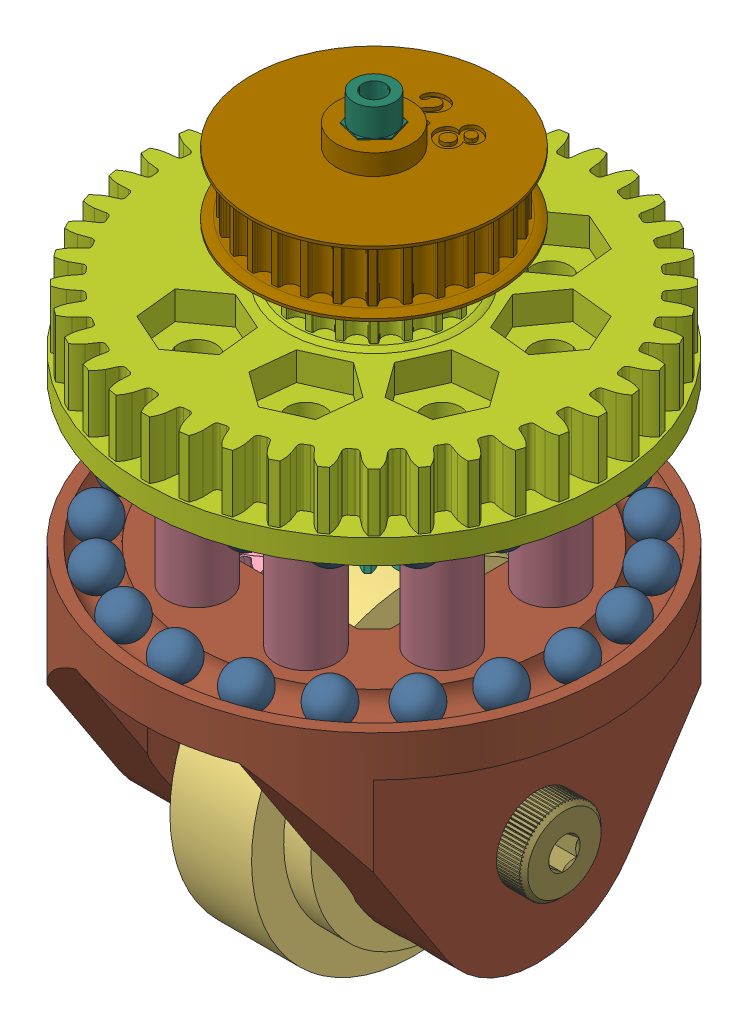
SolidWorks assembly Coaxial-Swerve Inner Modual Test Assem, configuration Default. Lengths in mm.
Overall size (53.98 92.63 53.98).
65 component instances, 18 part files, 64 mates.
Components (placement in the parent):
- Coaxial-Swerve test-1: Coaxial-Swerve test [Default] at origin size (78.17 85.72 76.44) (hidden)
- 57155K352_Stainless Steel Ball Bearing-1: 57155K352_Stainless Steel Ball Bearing [57155K352] at (-12.7 7.6375 0) x (1 0 0) z (0 -1 0) size (7.94 7.94 2.78)
- 60355K502_Ball Bearing-1: 60355K502_Ball Bearing [60355K502] at (-12.7 39.0049 0) x (1 0 0) z (0 -1 0) size (12.7 12.7 3.97)
- wheel bevel gear-2: wheel bevel gear [Hub and Gear] at (-5.2165 0 0) x (-1 0 0) z (0 -0.800175 0.599767) size (17.39 32.09 32.09)
- wheel bevel pinion-2: wheel bevel pinion [Inch - Straight bevel pinion 32DP15PT 40GT 20PA .25FW ---15O3H.063MD0.1875N] at (-12.7 16.1735 0) x (0 -1 0) z (0.960661 0 -0.277724) size (7.15 13.7 13.78)
- Inside Powered Gear-1: Inside Powered Gear [Default] at (-12.7 28.575 0) x (-0.277724 0 -0.960661) z (0 1 0) size (14.29 14.36 13.21)
- Inside Powering Pinion-1: Inside Powering Pinion [Default] at (0 28.575 0) x (-0.686506 0 0.727124) z (0 1 0) size (14.29 14.36 24.33)
- Swivel Base Gear-1: Swivel Base Gear [Default] at (0 41.783 0) x (0 0 1) z (0 1 0) size (53.98 53.98 14.13)
- 60355K503_Ball Bearing (1)-1: 60355K503_Ball Bearing (1) [60355K503] at (0 44.0563 0) x (1 0 0) z (0 -1 0) size (15.88 15.88 4.98)
- Above Driven Pully-1: Above Driven Pully [Default] at (0 56.515 0) x (0.972961 0 0.23097) z (-0.23097 0 0.972961) size (28.62 10.01 28.62)
- 9613K15_Wear-Resistant Nylon Balls-1: 9613K15_Wear-Resistant Nylon Balls [9613K15] at (-23.1902 20.3835 0) x (0.958311 0.024656 0.284661) z (-0.285108 0.016955 0.958346) size (4.76 4.76 4.76)
- 9613K15_Wear-Resistant Nylon Balls-2: 9613K15_Wear-Resistant Nylon Balls [9613K15] at (-23.1902 36.7665 0) size (4.76 4.76 4.76)
- 9613K15_Wear-Resistant Nylon Balls-3: 9613K15_Wear-Resistant Nylon Balls [9613K15] at (-22.0552 36.7665 7.1662) x (0.951057 0 -0.309017) z (0.309017 0 0.951057) size (4.76 4.76 4.76)
- 9613K15_Wear-Resistant Nylon Balls-4: 9613K15_Wear-Resistant Nylon Balls [9613K15] at (-18.7613 36.7665 13.6309) x (0.809017 0 -0.587785) z (0.587785 0 0.809017) size (4.76 4.76 4.76)
- 9613K15_Wear-Resistant Nylon Balls-5: 9613K15_Wear-Resistant Nylon Balls [9613K15] at (-13.6309 36.7665 18.7613) x (0.587785 0 -0.809017) z (0.809017 0 0.587785) size (4.76 4.76 4.76)
- 9613K15_Wear-Resistant Nylon Balls-6: 9613K15_Wear-Resistant Nylon Balls [9613K15] at (-7.1662 36.7665 22.0552) x (0.309017 0 -0.951057) z (0.951057 0 0.309017) size (4.76 4.76 4.76)
- 9613K15_Wear-Resistant Nylon Balls-7: 9613K15_Wear-Resistant Nylon Balls [9613K15] at (0 36.7665 23.1902) x (0 0 -1) z (1 0 0) size (4.76 4.76 4.76)
- 9613K15_Wear-Resistant Nylon Balls-8: 9613K15_Wear-Resistant Nylon Balls [9613K15] at (7.1662 36.7665 22.0552) x (-0.309017 0 -0.951057) z (0.951057 0 -0.309017) size (4.76 4.76 4.76)
- 9613K15_Wear-Resistant Nylon Balls-9: 9613K15_Wear-Resistant Nylon Balls [9613K15] at (13.6309 36.7665 18.7613) x (-0.587785 0 -0.809017) z (0.809017 0 -0.587785) size (4.76 4.76 4.76)
- 9613K15_Wear-Resistant Nylon Balls-10: 9613K15_Wear-Resistant Nylon Balls [9613K15] at (18.7613 36.7665 13.6309) x (-0.809017 0 -0.587785) z (0.587785 0 -0.809017) size (4.76 4.76 4.76)
- 9613K15_Wear-Resistant Nylon Balls-11: 9613K15_Wear-Resistant Nylon Balls [9613K15] at (22.0552 36.7665 7.1662) x (-0.951057 0 -0.309017) z (0.309017 0 -0.951057) size (4.76 4.76 4.76)
- 9613K15_Wear-Resistant Nylon Balls-12: 9613K15_Wear-Resistant Nylon Balls [9613K15] at (23.1902 36.7665 0) x (-1 0 0) z (0 0 -1) size (4.76 4.76 4.76)
- 9613K15_Wear-Resistant Nylon Balls-13: 9613K15_Wear-Resistant Nylon Balls [9613K15] at (22.0552 36.7665 -7.1662) x (-0.951057 0 0.309017) z (-0.309017 0 -0.951057) size (4.76 4.76 4.76)
- 9613K15_Wear-Resistant Nylon Balls-14: 9613K15_Wear-Resistant Nylon Balls [9613K15] at (18.7613 36.7665 -13.6309) x (-0.809017 0 0.587785) z (-0.587785 0 -0.809017) size (4.76 4.76 4.76)
- 9613K15_Wear-Resistant Nylon Balls-15: 9613K15_Wear-Resistant Nylon Balls [9613K15] at (13.6309 36.7665 -18.7613) x (-0.587785 0 0.809017) z (-0.809017 0 -0.587785) size (4.76 4.76 4.76)
- 9613K15_Wear-Resistant Nylon Balls-16: 9613K15_Wear-Resistant Nylon Balls [9613K15] at (7.1662 36.7665 -22.0552) x (-0.309017 0 0.951057) z (-0.951057 0 -0.309017) size (4.76 4.76 4.76)
- 9613K15_Wear-Resistant Nylon Balls-17: 9613K15_Wear-Resistant Nylon Balls [9613K15] at (0 36.7665 -23.1902) x (0 0 1) z (-1 0 0) size (4.76 4.76 4.76)
- 9613K15_Wear-Resistant Nylon Balls-18: 9613K15_Wear-Resistant Nylon Balls [9613K15] at (-7.1662 36.7665 -22.0552) x (0.309017 0 0.951057) z (-0.951057 0 0.309017) size (4.76 4.76 4.76)
- 9613K15_Wear-Resistant Nylon Balls-19: 9613K15_Wear-Resistant Nylon Balls [9613K15] at (-13.6309 36.7665 -18.7613) x (0.587785 0 0.809017) z (-0.809017 0 0.587785) size (4.76 4.76 4.76)
- 9613K15_Wear-Resistant Nylon Balls-20: 9613K15_Wear-Resistant Nylon Balls [9613K15] at (-18.7613 36.7665 -13.6309) x (0.809017 0 0.587785) z (-0.587785 0 0.809017) size (4.76 4.76 4.76)
- 9613K15_Wear-Resistant Nylon Balls-21: 9613K15_Wear-Resistant Nylon Balls [9613K15] at (-22.0552 36.7665 -7.1662) x (0.951057 0 0.309017) z (-0.309017 0 0.951057) size (4.76 4.76 4.76)
- 9613K15_Wear-Resistant Nylon Balls-22: 9613K15_Wear-Resistant Nylon Balls [9613K15] at (-22.0552 20.3835 7.1662) x (0.999373 0.024656 -0.025406) z (0.024992 0.016955 0.999544) size (4.76 4.76 4.76)
- 9613K15_Wear-Resistant Nylon Balls-23: 9613K15_Wear-Resistant Nylon Balls [9613K15] at (-18.7613 20.3835 13.6309) x (0.94261 0.024656 -0.332985) z (0.332645 0.016955 0.9429) size (4.76 4.76 4.76)
- 9613K15_Wear-Resistant Nylon Balls-24: 9613K15_Wear-Resistant Nylon Balls [9613K15] at (-13.6309 20.3835 18.7613) x (0.793577 0.024656 -0.60797) z (0.607736 0.016955 0.793958) size (4.76 4.76 4.76)
- 9613K15_Wear-Resistant Nylon Balls-25: 9613K15_Wear-Resistant Nylon Balls [9613K15] at (-7.1662 20.3835 22.0552) x (0.566863 0.024656 -0.823443) z (0.823338 0.016955 0.567298) size (4.76 4.76 4.76)
- 9613K15_Wear-Resistant Nylon Balls-26: 9613K15_Wear-Resistant Nylon Balls [9613K15] at (0 20.3835 23.1902) x (0.284661 0.024656 -0.958311) z (0.958346 0.016955 0.285108) size (4.76 4.76 4.76)
- 9613K15_Wear-Resistant Nylon Balls-27: 9613K15_Wear-Resistant Nylon Balls [9613K15] at (7.1662 20.3835 22.0552) x (-0.025406 0.024656 -0.999373) z (0.999544 0.016955 -0.024992) size (4.76 4.76 4.76)
- 9613K15_Wear-Resistant Nylon Balls-28: 9613K15_Wear-Resistant Nylon Balls [9613K15] at (13.6309 20.3835 18.7613) x (-0.332985 0.024656 -0.94261) z (0.9429 0.016955 -0.332645) size (4.76 4.76 4.76)
- 9613K15_Wear-Resistant Nylon Balls-29: 9613K15_Wear-Resistant Nylon Balls [9613K15] at (18.7613 20.3835 13.6309) x (-0.60797 0.024656 -0.793577) z (0.793958 0.016955 -0.607736) size (4.76 4.76 4.76)
- 9613K15_Wear-Resistant Nylon Balls-30: 9613K15_Wear-Resistant Nylon Balls [9613K15] at (22.0552 20.3835 7.1662) x (-0.823443 0.024656 -0.566863) z (0.567298 0.016955 -0.823338) size (4.76 4.76 4.76)
- 9613K15_Wear-Resistant Nylon Balls-31: 9613K15_Wear-Resistant Nylon Balls [9613K15] at (23.1902 20.3835 0) x (-0.958311 0.024656 -0.284661) z (0.285108 0.016955 -0.958346) size (4.76 4.76 4.76)
- 9613K15_Wear-Resistant Nylon Balls-32: 9613K15_Wear-Resistant Nylon Balls [9613K15] at (22.0552 20.3835 -7.1662) x (-0.999373 0.024656 0.025406) z (-0.024992 0.016955 -0.999544) size (4.76 4.76 4.76)
- 9613K15_Wear-Resistant Nylon Balls-33: 9613K15_Wear-Resistant Nylon Balls [9613K15] at (18.7613 20.3835 -13.6309) x (-0.94261 0.024656 0.332985) z (-0.332645 0.016955 -0.9429) size (4.76 4.76 4.76)
- 9613K15_Wear-Resistant Nylon Balls-34: 9613K15_Wear-Resistant Nylon Balls [9613K15] at (13.6309 20.3835 -18.7613) x (-0.793577 0.024656 0.60797) z (-0.607736 0.016955 -0.793958) size (4.76 4.76 4.76)
- 9613K15_Wear-Resistant Nylon Balls-35: 9613K15_Wear-Resistant Nylon Balls [9613K15] at (7.1662 20.3835 -22.0552) x (-0.566863 0.024656 0.823443) z (-0.823338 0.016955 -0.567298) size (4.76 4.76 4.76)
- 9613K15_Wear-Resistant Nylon Balls-36: 9613K15_Wear-Resistant Nylon Balls [9613K15] at (0 20.3835 -23.1902) x (-0.284661 0.024656 0.958311) z (-0.958346 0.016955 -0.285108) size (4.76 4.76 4.76)
- 9613K15_Wear-Resistant Nylon Balls-37: 9613K15_Wear-Resistant Nylon Balls [9613K15] at (-7.1662 20.3835 -22.0552) x (0.025406 0.024656 0.999373) z (-0.999544 0.016955 0.024992) size (4.76 4.76 4.76)
- 9613K15_Wear-Resistant Nylon Balls-38: 9613K15_Wear-Resistant Nylon Balls [9613K15] at (-13.6309 20.3835 -18.7613) x (0.332985 0.024656 0.94261) z (-0.9429 0.016955 0.332645) size (4.76 4.76 4.76)
- 9613K15_Wear-Resistant Nylon Balls-39: 9613K15_Wear-Resistant Nylon Balls [9613K15] at (-18.7613 20.3835 -13.6309) x (0.60797 0.024656 0.793577) z (-0.793958 0.016955 0.607736) size (4.76 4.76 4.76)
- 9613K15_Wear-Resistant Nylon Balls-40: 9613K15_Wear-Resistant Nylon Balls [9613K15] at (-22.0552 20.3835 -7.1662) x (0.823443 0.024656 0.566863) z (-0.567298 0.016955 0.823338) size (4.76 4.76 4.76)
- Wheel Container-1: Wheel Container [Default] at (0 17.7482 0) size (53.98 32.83 53.98)
- 60355K503_Ball Bearing (1)-2: 60355K503_Ball Bearing (1) [60355K503] at (5.35 0 0) x (0 -1 0) z (-1 0 0) size (15.88 15.88 4.98)
- 60355K503_Ball Bearing (1)-3: 60355K503_Ball Bearing (1) [60355K503] at (-5.4285 0 0) x (0 -1 0) z (-1 0 0) size (15.88 15.88 4.98)
- 91259A544_Alloy Steel Shoulder Screw-1: 91259A544_Alloy Steel Shoulder Screw [91259A544] at (-0.8065 0 0) x (0 -0.924225 -0.381849) z (1 0 0) size (9.53 9.53 46.56)
- Inner Swerve Spacer-1: Inner Swerve Spacer [Default] at (-6.35 28.575 14.2875) size (6.99 16.89 6.99)
- Inner Swerve Spacer-2: Inner Swerve Spacer [Default] at (6.35 28.575 14.2875) x (0.982082 0 -0.188455) z (0.188455 0 0.982082) size (6.99 16.89 6.99)
- Inner Swerve Spacer-3: Inner Swerve Spacer [Default] at (14.2875 28.575 6.35) x (0.918365 0 -0.395734) z (0.395734 0 0.918365) size (6.99 16.89 6.99)
- Inner Swerve Spacer-4: Inner Swerve Spacer [Default] at (14.2875 28.575 -6.35) x (0.8 0 -0.6) z (0.6 0 0.8) size (6.99 16.89 6.99)
- Inner Swerve Spacer-5: Inner Swerve Spacer [Default] at (6.35 28.575 -14.2875) x (0.63358 0 -0.773678) z (0.773678 0 0.63358) size (6.99 16.89 6.99)
- Inner Swerve Spacer-6: Inner Swerve Spacer [Default] at (-6.35 28.575 -14.2875) x (0.325934 0 -0.945392) z (0.945392 0 0.325934) size (6.99 16.89 6.99)
- wheel bevel gear-3: wheel bevel gear [Tire] at (-5.2165 0 0) x (-1 0 0) z (0 -0.800175 0.599767) size (9.53 38.1 38.1)
- Swerve Stage 3 Drive Shaft-1: Swerve Stage 3 Drive Shaft [Default] at (-12.7 23.0219 0) x (-0.970819 0 -0.239814) z (0.239814 0 -0.970819) size (5.5 34.34 4.76)
- Swerve Stage 2 Drive Shaft-1: Swerve Stage 2 Drive Shaft [Default] at (0 44.0944 0) x (0.686506 0 -0.727124) z (0.727124 0 0.686506) size (5.5 40.56 4.76)
- Sput to Bevel Gear Spacer-1: Sput to Bevel Gear Spacer [Default] at (-12.7 19.9963 0) size (6.99 7.65 6.99)
- Inside Pullies Spacer-1: Inside Pullies Spacer [Default] at (0 49.6316 0) size (8.26 6.17 8.26)
Mates (geometry in assembly coordinates):
- Coincident1: coincident aligned: plane of Coaxial-Swerve test-1 through (0 0 0) normal (0 0 1)
- Coincident2: coincident aligned: plane of Coaxial-Swerve test-1 through (0 0 0) normal (0 1 0)
- Coincident3: coincident aligned: plane of Coaxial-Swerve test-1 through (0 0 0) normal (1 0 0)
- Concentric3: concentric anti-aligned: line of Coaxial-Swerve test-1 through (31.4642 -12.7 9.525) axis (0 0 1); cylinder of 60355K502_Ball Bearing-1 through (-12.7 37.0205 0) axis (0 -1 0) radius 2.3813
- Coincident11: coincident: line of Coaxial-Swerve test-1 through (12.7 -19.05 40.9892) axis (0 1 0); plane of 60355K502_Ball Bearing-1 through (-12.7 40.9892 6.1516) normal (0 1 0)
- Concentric4: concentric anti-aligned: line of Coaxial-Swerve test-1 through (3.175 -12.7 6.35) axis (0 0 1); cylinder of 57155K352_Stainless Steel Ball Bearing-1 through (-12.7 6.2484 0) axis (0 -1 0) radius 2.3813
- Coincident13: coincident anti-aligned: plane of Wheel Container-1 through (-12.7 6.2484 0) normal (0 1 0); plane of 57155K352_Stainless Steel Ball Bearing-1 through (-12.7 6.2484 3.8298) normal (0 -1 0)
- Concentric7: concentric aligned: line of Coaxial-Swerve test-1 through (31.4642 -12.7 9.525) axis (0 0 1); cylinder of wheel bevel pinion-2 through (-12.7 9.0238 0) axis (0 1 0) radius 3.2257
- Concentric8: concentric aligned: line of Coaxial-Swerve test-1 through (0 1.7015 -6.464) axis (0 0 1); cylinder of wheel bevel gear-2 through (-9.4469 0 0) axis (1 0 0) radius 3.81
- Coincident18: coincident: point of wheel bevel gear-2; point of wheel bevel pinion-2
- Concentric9: concentric anti-aligned: line of Coaxial-Swerve test-1 through (31.4642 -12.7 9.525) axis (0 0 1); cylinder of Inside Powered Gear-1 through (-12.7 37.0205 0) axis (0 -1 0) radius 3.81
- Coincident20: coincident: line of Coaxial-Swerve test-1 through (3.81 -23.1902 28.575) axis (0 1 0); plane of Inside Powered Gear-1 through (-12.7 28.575 0) normal (0 1 0)
- Concentric11: concentric anti-aligned: line of Coaxial-Swerve test-1 through (44.45 0 22.225) axis (0 0 1); cylinder of Inside Powering Pinion-1 through (0 46.5582 0) axis (0 -1 0) radius 3.175
- Coincident23: coincident: line of Coaxial-Swerve test-1 through (3.81 -23.1902 28.575) axis (0 1 0); plane of Inside Powering Pinion-1 through (0 28.575 0) normal (0 1 0)
- Coincident24: coincident aligned: plane of wheel bevel pinion-2 through (-12.7 16.1735 0) normal (-0.277724 0 -0.960661); plane of Inside Powered Gear-1 through (-12.7 28.575 0) normal (-0.277724 0 -0.960661)
- GearMate1: gear = 25.4 : 25.4 mm: cylinder of Inside Powered Gear-1 through (-12.7 37.0205 0) axis (0 -1 0) radius 3.81; cylinder of Inside Powering Pinion-1 through (0 46.5582 0) axis (0 -1 0) radius 3.175
- GearMate2: gear = 1016 : 381 mm: cylinder of wheel bevel pinion-2 through (-12.7 9.0238 0) axis (0 1 0) radius 3.2257; cylinder of wheel bevel gear-2 through (-9.4469 0 0) axis (1 0 0) radius 3.81
- Concentric12: concentric aligned: line of Coaxial-Swerve test-1 through (44.45 0 22.225) axis (0 0 1); cylinder of Swivel Base Gear-1 through (0 51.1493 0) axis (0 1 0) radius 7.9375
- Coincident27: coincident: line of Coaxial-Swerve test-1 through (54.0004 27.0002 37.0205) axis (0 -1 0); plane of Swivel Base Gear-1 through (0 37.0205 0) normal (0 -1 0)
- Concentric13: concentric anti-aligned: line of Coaxial-Swerve test-1 through (9.525 0 37.0205) axis (0 0 1); cylinder of 60355K503_Ball Bearing (1)-1 through (0 41.5671 0) axis (0 -1 0) radius 3.175
- Coincident28: coincident: line of Coaxial-Swerve test-1 through (15.875 -7.9375 46.5455) axis (0 1 0); plane of 60355K503_Ball Bearing (1)-1 through (0 46.5455 7.6886) normal (0 1 0)
- Concentric14: concentric aligned: cylinder of 60355K502_Ball Bearing-1 through (-12.7 37.0205 0) axis (0 -1 0) radius 6.35; cylinder of Swivel Base Gear-1 through (-12.7 41.0845 0) axis (0 -1 0) radius 6.35
- Concentric15: concentric aligned: line of Coaxial-Swerve test-1 through (44.45 0 22.225) axis (0 0 1); cylinder of Above Driven Pully-1 through (0 65.2463 0) axis (0 1 0) radius 14.3109
- Coincident29: coincident: plane of assembly; point of Coaxial-Swerve test-1; plane of Above Driven Pully-1 through (0 56.515 0) normal (0 1 0)
- Concentric16: concentric: sphere of assembly; point of Coaxial-Swerve test-1; sphere of 9613K15_Wear-Resistant Nylon Balls-2
- Concentric17: concentric: sphere of assembly; point of Coaxial-Swerve test-1; sphere of 9613K15_Wear-Resistant Nylon Balls-1
- Concentric18: concentric anti-aligned: line of Coaxial-Swerve test-1 through (44.45 0 22.225) axis (0 0 1); cylinder of Wheel Container-1 through (0 17.7482 0) axis (0 -1 0) radius 26.9875
- Coincident33: coincident: line of Coaxial-Swerve test-1 through (1.3657 -27.0002 20.1295) axis (0 1 0); plane of Wheel Container-1 through (-25.5872 20.1295 0) normal (0 1 0)
- Concentric19: concentric aligned: line of Coaxial-Swerve test-1 through (31.4642 -12.7 9.525) axis (0 0 1); cylinder of Wheel Container-1 through (-12.7 15.367 0) axis (0 1 0) radius 4.7625
- Concentric20: concentric anti-aligned: cylinder of wheel bevel gear-2 through (2.8608 0 0) axis (1 0 0) radius 7.9375; cylinder of 60355K503_Ball Bearing (1)-2 through (2.8608 0 0) axis (-1 0 0) radius 7.9375
- Coincident35: coincident anti-aligned: plane of wheel bevel gear-2 through (2.8608 0 0) normal (1 0 0); plane of 60355K503_Ball Bearing (1)-2 through (2.8608 0 7.6886) normal (-1 0 0)
- Concentric21: concentric aligned: cylinder of wheel bevel gear-2 through (-2.9393 0 0) axis (-1 0 0) radius 7.9375; cylinder of 60355K503_Ball Bearing (1)-3 through (-7.9177 0 0) axis (-1 0 0) radius 7.9375
- Coincident36: coincident anti-aligned: plane of wheel bevel gear-2 through (-2.9393 0 0) normal (-1 0 0); plane of 60355K503_Ball Bearing (1)-3 through (-2.9393 0 7.6886) normal (1 0 0)
- Concentric22: concentric: cylinder of Wheel Container-1 through (-26.9875 0 0) axis (1 0 0) radius 3.175; cylinder of 91259A546_Alloy Steel Shoulder Screw-1 through (-23.8125 0 0) axis (-1 0 0) radius 3.175
- Coincident37: coincident anti-aligned: plane of Wheel Container-1 through (-19.05 -35.433 19.116) normal (-1 0 0); plane of 91259A546_Alloy Steel Shoulder Screw-1 through (-19.05 4.7625 0) normal (1 0 0)
- Concentric23: concentric aligned: cylinder of Wheel Container-1 through (-26.9875 0 0) axis (1 0 0) radius 3.175; cylinder of 91259A544_Alloy Steel Shoulder Screw-1 through (22.2123 0 0) axis (1 0 0) radius 3.175
- Coincident38: coincident anti-aligned: plane of Wheel Container-1 through (17.4498 0 0) normal (1 0 0); plane of 91259A544_Alloy Steel Shoulder Screw-1 through (17.4498 1.8186 -4.4016) normal (-1 0 0)
- Coincident41: coincident anti-aligned: plane of Wheel Container-1 through (0 20.1295 0) normal (0 1 0); plane of Inner Swerve Spacer-1 through (-6.35 20.1295 14.2875) normal (0 -1 0)
- Coincident42: coincident anti-aligned: plane of Wheel Container-1 through (0 20.1295 0) normal (0 1 0); plane of Inner Swerve Spacer-2 through (6.35 20.1295 14.2875) normal (0 -1 0)
- Coincident43: coincident anti-aligned: plane of Wheel Container-1 through (0 20.1295 0) normal (0 1 0); plane of Inner Swerve Spacer-3 through (14.2875 20.1295 6.35) normal (0 -1 0)
- Coincident44: coincident anti-aligned: plane of Wheel Container-1 through (0 20.1295 0) normal (0 1 0); plane of Inner Swerve Spacer-4 through (14.2875 20.1295 -6.35) normal (0 -1 0)
- Coincident45: coincident anti-aligned: plane of Wheel Container-1 through (0 20.1295 0) normal (0 1 0); plane of Inner Swerve Spacer-5 through (6.35 20.1295 -14.2875) normal (0 -1 0)
- Coincident46: coincident anti-aligned: plane of Wheel Container-1 through (0 20.1295 0) normal (0 1 0); plane of Inner Swerve Spacer-6 through (-6.35 20.1295 -14.2875) normal (0 -1 0)
- Concentric24: concentric anti-aligned: cylinder of Wheel Container-1 through (-6.35 -12.7 14.2875) axis (0 1 0) radius 2.159; cylinder of Inner Swerve Spacer-1 through (-6.35 37.0205 14.2875) axis (0 -1 0) radius 2.159
- Concentric25: concentric anti-aligned: cylinder of Wheel Container-1 through (6.35 -12.7 14.2875) axis (0 1 0) radius 2.159; cylinder of Inner Swerve Spacer-2 through (6.35 37.0205 14.2875) axis (0 -1 0) radius 2.159
- Concentric26: concentric anti-aligned: cylinder of Wheel Container-1 through (14.2875 -12.7 6.35) axis (0 1 0) radius 2.159; cylinder of Inner Swerve Spacer-3 through (14.2875 37.0205 6.35) axis (0 -1 0) radius 2.159
- Concentric27: concentric anti-aligned: cylinder of Wheel Container-1 through (14.2875 -12.7 -6.35) axis (0 1 0) radius 2.159; cylinder of Inner Swerve Spacer-4 through (14.2875 37.0205 -6.35) axis (0 -1 0) radius 2.159
- Concentric28: concentric anti-aligned: cylinder of Wheel Container-1 through (6.35 -12.7 -14.2875) axis (0 1 0) radius 2.159; cylinder of Inner Swerve Spacer-5 through (6.35 37.0205 -14.2875) axis (0 -1 0) radius 2.159
- Concentric29: concentric anti-aligned: cylinder of Wheel Container-1 through (-6.35 -12.7 -14.2875) axis (0 1 0) radius 2.159; cylinder of Inner Swerve Spacer-6 through (-6.35 37.0205 -14.2875) axis (0 -1 0) radius 2.159
- Coincident49: coincident anti-aligned: circle of Coaxial-Swerve test-1; cylinder of brushless drive motor-2 through (-36.8902 36.5125 -9.525) axis (0 -1 0) radius 10.9728
- Coincident59: coincident aligned: plane of wheel bevel gear-2 through (-5.2165 0 0) normal (0 -0.800175 0.599767); plane of wheel bevel gear-3 through (-5.2165 0 0) normal (0 -0.800175 0.599767)
- Coincident60: coincident aligned: plane of wheel bevel gear-2 through (-5.2165 0 0) normal (0 -0.599767 -0.800175); plane of wheel bevel gear-3 through (-5.2165 0 0) normal (0 -0.599767 -0.800175)
- Coincident61: coincident aligned: plane of wheel bevel gear-2 through (-5.2165 0 0) normal (-1 0 0); plane of wheel bevel gear-3 through (-5.2165 0 0) normal (-1 0 0)
- Concentric30: concentric anti-aligned: cylinder of 57155K352_Stainless Steel Ball Bearing-1 through (-12.7 6.2484 0) axis (0 -1 0) radius 2.3813; cylinder of Swerve Stage 3 Drive Shaft-1 through (-12.7 5.8515 0) axis (0 1 0) radius 2.3813
- Coincident62: coincident anti-aligned: plane of 57155K352_Stainless Steel Ball Bearing-1 through (-12.7 9.0265 3.8298) normal (0 1 0); plane of Swerve Stage 3 Drive Shaft-1 through (-12.7 9.0265 0) normal (0 -1 0)
- Coincident63: coincident anti-aligned: plane of Inside Powering Pinion-1 through (0 25.4 0) normal (0 1 0); plane of Swerve Stage 2 Drive Shaft-1 through (0 25.4 0) normal (0 -1 0)
- Concentric31: concentric aligned: cylinder of Above Driven Pully-1 through (0 65.2463 0) axis (0 1 0) radius 4.3561; cylinder of Swerve Stage 2 Drive Shaft-1 through (0 59.6138 0) axis (0 1 0) radius 1.3526
- Parallel1: parallel anti-aligned: plane of Above Driven Pully-1 through (2.7538 62.7126 0.6537) normal (-0.727124 0 -0.686506); plane of Swerve Stage 2 Drive Shaft-1 through (0.7876 62.7888 2.6344) normal (0.727124 0 0.686506)
- Parallel2: parallel anti-aligned: plane of Inside Powered Gear-1 through (-11.9241 23.8125 2.6837) normal (-0.720847 0 -0.693094); plane of Swerve Stage 3 Drive Shaft-1 through (-11.9364 37.0173 2.6415) normal (0.720847 0 0.693094)
- Parallel3: parallel anti-aligned: plane of Inside Powering Pinion-1 through (-0.8002 22.225 -2.6766) normal (0.727124 0 0.686506); plane of Swerve Stage 2 Drive Shaft-1 through (-0.7876 62.7888 -2.6344) normal (-0.727124 0 -0.686506)
- Coincident67: coincident anti-aligned: plane of wheel bevel pinion-2 through (-12.7 16.1736 0) normal (0 1 0); plane of Sput to Bevel Gear Spacer-1 through (-12.7 16.1736 0) normal (0 -1 0)
- Concentric33: concentric aligned: cylinder of Inside Powered Gear-1 through (-12.7 37.0205 0) axis (0 -1 0) radius 3.81; cylinder of Sput to Bevel Gear Spacer-1 through (-12.7 23.819 0) axis (0 -1 0) radius 3.4925
- Coincident68: coincident anti-aligned: plane of 60355K503_Ball Bearing (1)-1 through (0 46.5455 3.4239) normal (0 1 0); plane of Inside Pullies Spacer-1 through (0 46.5455 0) normal (0 -1 0)
- Concentric34: concentric aligned: cylinder of Inside Powering Pinion-1 through (0 46.5582 0) axis (0 -1 0) radius 3.175; cylinder of Inside Pullies Spacer-1 through (0 52.7177 0) axis (0 -1 0) radius 4.1275
